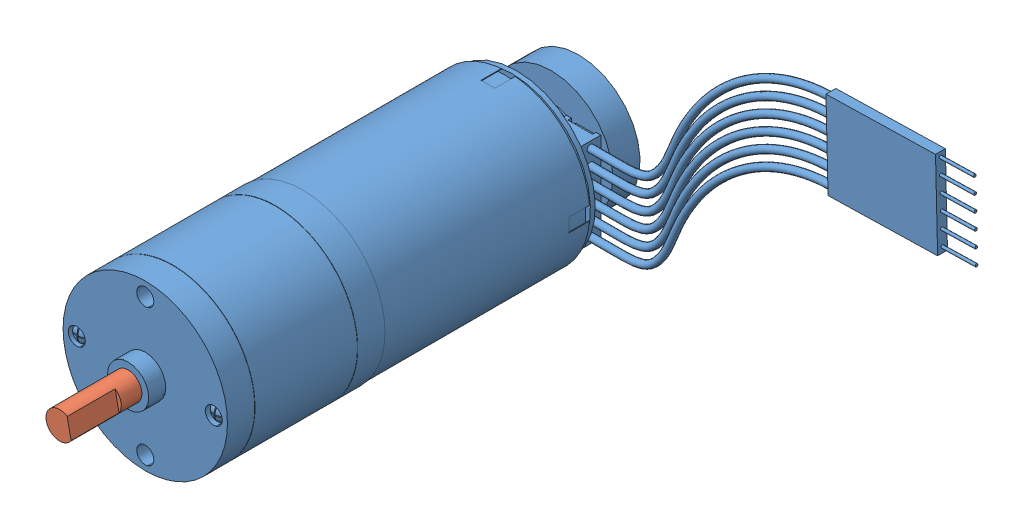
SolidWorks assembly MotoreductorEncoder, configuration Predeterminado. Lengths in mm.
Overall size (77.69 42.72 76.25).
2 component instances, 2 part files, 2 mates.
Components (placement in the parent):
- Motoreductor-3: Motoreductor [Predeterminado] at (28.2679 2.4302 85.7846) x (0 0 -1) z (0 1 0) size (66.25 77.69 42.72)
- Flecha-1: Flecha [Predeterminado] at (28.2679 2.4302 88.2846) x (0.833649 -0.552294 0) z (0 0 1) size (4 4 10)
Mates (geometry in assembly coordinates):
- Coincidente4: coincident anti-aligned: plane of Motoreductor-3 through (28.2679 2.4302 88.2846) normal (0 0 1); plane of Flecha-1 through (28.2679 2.4302 88.2846) normal (0 0 -1)
- Concéntrica2: concentric aligned: circle of Motoreductor-3; circle of Flecha-1
